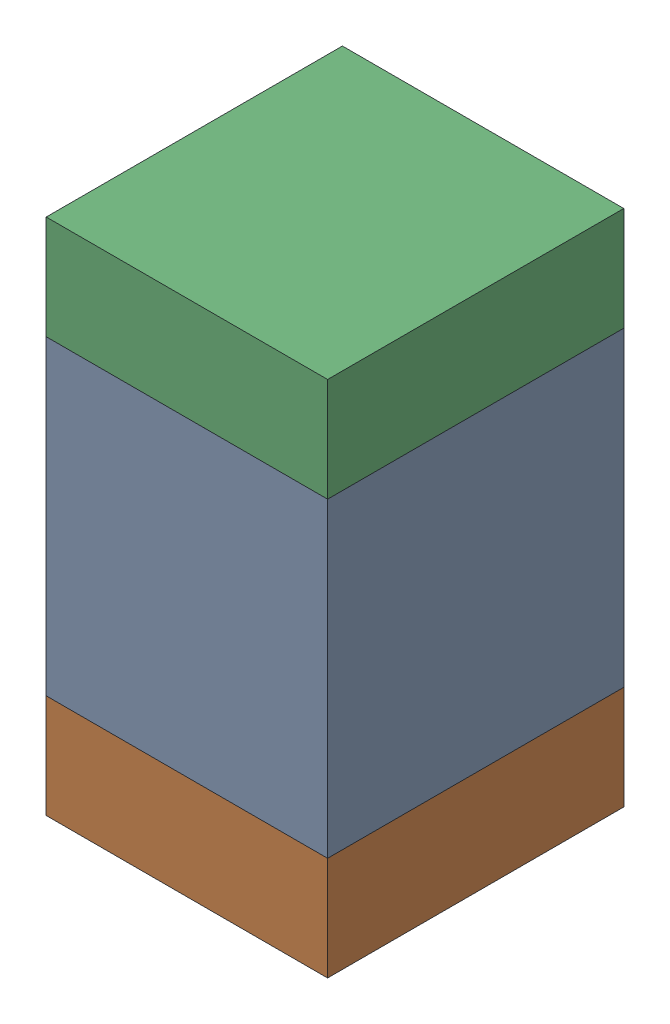
SolidWorks assembly C7, configuration Default. Lengths in mm.
Overall size (0.95 1.75 1).
6 component instances, 2 part files, 0 mates.
Components (placement in the parent):
- 959208528-1: 959208528 [Default] at (145.288 83.8282 0) size (0.95 1.05 1)
  - Extruded-15-1: Extruded-15 [Default] at origin size (0.95 1.05 1)
- 959208664-1: 959208664 [Default] at (145.288 83.1282 0) size (0.95 0.35 1)
  - Extruded-14-1: Extruded-14 [Default] at origin size (0.95 0.35 1)
- 959208664-2: 959208664 [Default] at (145.288 84.5282 0) size (0.95 0.35 1)
  - Extruded-14-1: Extruded-14 [Default] at origin size (0.95 0.35 1)
